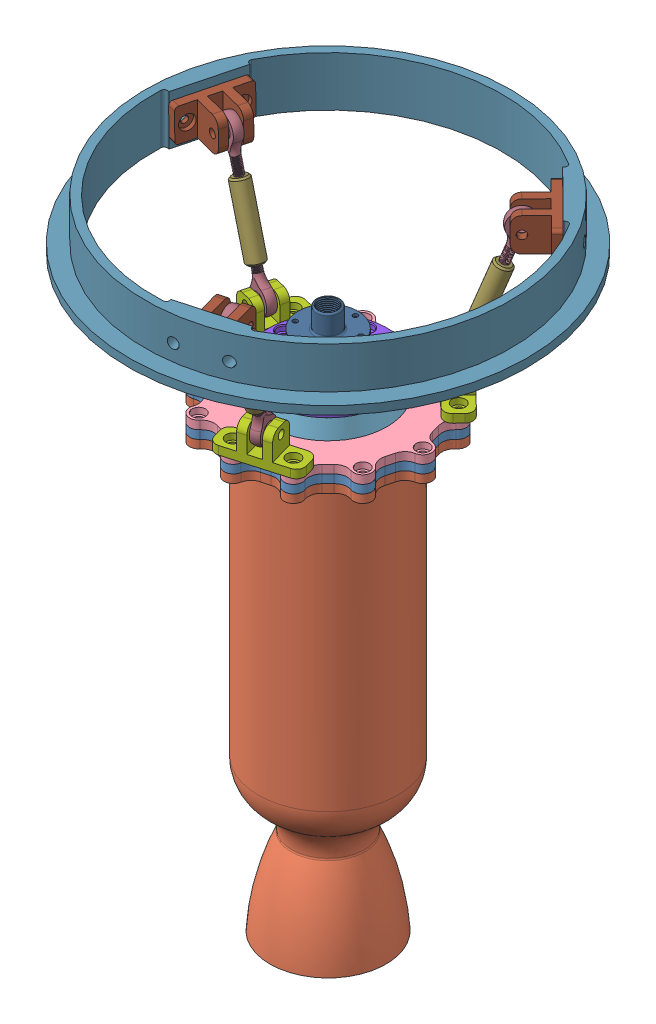
SolidWorks assembly 000014-R02_REMOVE_BEFORE_FLIGHT_ASSM, configuration Default. Lengths in mm.
Overall size (431.04 487.19 431.04).
30 component instances, 14 part files, 22 mates.
Components (placement in the parent):
- 000030-R02_FILM_COOLING_VOLUTE-2: 000030-R02_FILM_COOLING_VOLUTE [Default] at (-8.7806 254.8412 0) x (-0.965926 0 -0.258819) z (0.258819 0 -0.965926) size (156.79 34.88 257.08)
- 000001-R05_RBF_TCA-2: 000001-R05_RBF_TCA [Default] at (-8.7806 -14.701 0) x (0 -1 0) z (0 0 1) size (343.5 185.64 158.75)
- 000015-R05_PINTLE_INJECT_ASSM-1: 000015-R05_PINTLE_INJECT_ASSM [Default] at (86.4435 164.1172 71.5928) x (-0.866025 0 0.5) z (-0.5 0 -0.866025) size (158.75 36.86 158.75)
  - 000033-R01_PINTLE_BOTTOM_PLATE-1: 000033-R01_PINTLE_BOTTOM_PLATE [Default] at (46.67 88.1839 109.6132) size (87.7 15.24 87.7)
  - 000032-R02_PINTLE_MIDDLE_PLATE-1: 000032-R02_PINTLE_MIDDLE_PLATE [Default] at (46.67 92.7382 109.6132) size (158.75 29.57 158.75)
  - 000031-R01_PINTLE_UPPER_PLATE-1: 000031-R01_PINTLE_UPPER_PLATE [Default] at (46.67 125.0393 109.6132) size (90.17 15.27 90.17)
  - MISUMI_MSBH6-20-1: MISUMI_MSBH6-20 [Default] at (8.57 121.0393 109.6132) x (0 -1 0) z (0 0 1) size (31 9 9)
- engine-side-clevis-1: engine-side-clevis [Default] at (-7.5695 273.8912 0.6838) x (0.693392 0 -0.72056) z (0.72056 0 0.693392) size (19.05 25.4 57.15)
- 000012_R04_ASI_ASSEM-1: 000012_R04_ASI_ASSEM [Default] at (-8.7806 251.1654 0) x (-0.959573 0 0.281459) z (-0.281459 0 -0.959573) size (117.68 93.77 117.68)
  - 000011-R02_ASI_TOP-1: 000011-R02_ASI_TOP [Default] at (0 37.9912 0) x (-0.924896 0 -0.380219) z (0.380219 0 -0.924896) size (90.17 60.14 90.17)
  - 000011-R02_ASI_BOTTOM-1: 000011-R02_ASI_BOTTOM [Default] at (0 4.4632 0) x (0.915191 0 -0.40302) z (0.40302 0 0.915191) size (30.48 24.13 30.48)
  - 000010-R02_ASI-1: 000010-R02_ASI [Default] at (0 63.3912 0) x (-0.133168 0 -0.991093) z (0.991093 0 -0.133168) size (45.72 18.88 45.72)
- 000061-R01_THRUST_MOUNT_ASSM-6: 000061-R01_THRUST_MOUNT_ASSM [Default] at (108.3978 328.6699 -153.5919) x (-0.197262 0.979436 -0.042345) z (0.576802 0.15088 0.802829) size (118.32 96.83 60.51) (flexible)
  - 000029-R01_LAUNCH_MOUNT_CLEVIS-1: 000029-R01_LAUNCH_MOUNT_CLEVIS [Default] at (58.7034 52.1122 43.2404) x (0.980239 -0.133241 0.146211) z (-0.165429 -0.146887 0.975222) size (31.75 38.1 50.8)
  - THREADED_ROD-1: THREADED_ROD [Default] at (36.9792 86.6959 44.7642) x (0.299604 0.419939 -0.856673) z (0.366938 0.778134 0.509768) size (12.7 50.8 12.7)
  - 8405K111_THRUST-RATED BALL JOINT ROD END-1: 8405K111_THRUST-RATED BALL JOINT ROD END [8405K111] at (-12.0929 112.7217 40.36) x (0.441581 0.869836 0.219984) z (-0.171501 -0.158832 0.972296) size (19.88 46.6 9.53)
  - 8405K111_THRUST-RATED BALL JOINT ROD END-2: 8405K111_THRUST-RATED BALL JOINT ROD END [8405K111] at (47.1332 81.3106 45.6756) x (-0.443891 -0.871932 -0.206628) z (-0.165429 -0.146887 0.975222) size (19.88 46.6 9.53)
- engine-side-clevis-6: engine-side-clevis [Default] at (-9.9782 273.8912 0.7069) x (0.277328 0 0.960775) z (-0.960775 0 0.277328) size (19.05 25.4 57.15)
- engine-side-clevis-7: engine-side-clevis [Default] at (-8.7939 273.8912 -1.3907) x (-0.97072 0 -0.240215) z (0.240215 0 -0.97072) size (19.05 25.4 57.15)
- 000061-R01_THRUST_MOUNT_ASSM-7: 000061-R01_THRUST_MOUNT_ASSM [Default] at (65.6447 328.6699 178.2754) x (0.135303 0.979436 -0.149661) z (-0.983671 0.15088 0.098111) size (118.32 96.83 60.51) (flexible)
  - 000029-R01_LAUNCH_MOUNT_CLEVIS-1: 000029-R01_LAUNCH_MOUNT_CLEVIS [Default] at (58.7034 52.1122 43.2404) x (0.980239 -0.133241 0.146211) z (-0.165429 -0.146887 0.975222) size (31.75 38.1 50.8)
  - THREADED_ROD-1: THREADED_ROD [Default] at (36.7589 86.8127 44.7445) x (0.039613 0.238881 0.97024) z (-0.472056 -0.851338 0.22888) size (12.7 50.8 12.7)
  - 8405K111_THRUST-RATED BALL JOINT ROD END-1: 8405K111_THRUST-RATED BALL JOINT ROD END [8405K111] at (-12.0929 112.7217 40.36) x (0.441581 0.869836 0.219984) z (-0.171501 -0.158832 0.972296) size (19.88 46.6 9.53)
  - 8405K111_THRUST-RATED BALL JOINT ROD END-2: 8405K111_THRUST-RATED BALL JOINT ROD END [8405K111] at (47.1332 81.3106 45.6756) x (-0.443891 -0.871932 -0.206628) z (-0.165429 -0.146887 0.975222) size (19.88 46.6 9.53)
- 000061-R01_THRUST_MOUNT_ASSM-8: 000061-R01_THRUST_MOUNT_ASSM [Default] at (-200.3842 328.6699 -24.6835) x (0.061959 0.979436 0.192007) z (0.406869 0.15088 -0.90094) size (124.54 97.67 60.51) (flexible)
  - 000029-R01_LAUNCH_MOUNT_CLEVIS-1: 000029-R01_LAUNCH_MOUNT_CLEVIS [Default] at (58.7034 52.1122 43.2404) x (-0.980239 0.133241 -0.146211) z (0.165429 0.146887 -0.975222) size (31.75 38.1 50.8)
  - THREADED_ROD-1: THREADED_ROD [Default] at (36.7628 86.8107 44.7448) x (0.181458 0.17849 -0.967065) z (0.437583 0.866015 0.241947) size (12.7 50.8 12.7)
  - 8405K111_THRUST-RATED BALL JOINT ROD END-1: 8405K111_THRUST-RATED BALL JOINT ROD END [8405K111] at (-12.0929 112.7217 40.36) x (0.441581 0.869836 0.219984) z (-0.171501 -0.158832 0.972296) size (19.88 46.6 9.53)
  - 8405K111_THRUST-RATED BALL JOINT ROD END-2: 8405K111_THRUST-RATED BALL JOINT ROD END [8405K111] at (47.1332 81.3106 45.6756) x (0.443891 0.871932 0.206628) z (0.165429 0.146887 -0.975222) size (19.88 46.6 9.53)
- 000066-R01_THRUST_MOUNT-1: 000066-R01_THRUST_MOUNT [Default] at (-8.7806 366.7438 0) x (0.702595 0 -0.71159) z (0.71159 0 0.702595) size (304.8 38.1 304.8)
Mates (geometry in assembly coordinates):
- Concentric22: concentric aligned: cylinder of 000030-R02_FILM_COOLING_VOLUTE-2 through (63.6094 267.5412 0) axis (0 1 0) radius 4; cylinder of 000001-R05_RBF_TCA-2 through (63.6094 261.1912 0) axis (0 1 0) radius 4
- Coincident11: coincident anti-aligned: plane of 000030-R02_FILM_COOLING_VOLUTE-2 through (-66.4686 261.1912 -15.4575) normal (0 -1 0); plane of 000001-R05_RBF_TCA-2 through (70.5944 261.1912 0) normal (0 1 0)
- Concentric40: concentric anti-aligned: cylinder of 000030-R02_FILM_COOLING_VOLUTE-2 through (-8.7806 299.8925 0) axis (0 1 0) radius 43.848; cylinder of 000015-R05_PINTLE_INJECT_ASSM-1/000033-R01_PINTLE_BOTTOM_PLATE-1 through (-8.7806 252.3012 0) axis (0 -1 0) radius 43.848
- Coincident29: coincident anti-aligned: plane of 000030-R02_FILM_COOLING_VOLUTE-2 through (-51.1345 267.5412 -11.3487) normal (0 1 0); plane of 000015-R05_PINTLE_INJECT_ASSM-1/000032-R02_PINTLE_MIDDLE_PLATE-1 through (-77.5213 267.5412 39.6875) normal (0 -1 0)
- Coincident65: coincident anti-aligned: plane of 000015-R05_PINTLE_INJECT_ASSM-1/000032-R02_PINTLE_MIDDLE_PLATE-1 through (-77.5213 273.8912 39.6875) normal (0 1 0); plane of engine-side-clevis-1 through (-7.5695 273.8912 0.6838) normal (0 -1 0)
- Coincident70: coincident anti-aligned: plane of 000015-R05_PINTLE_INJECT_ASSM-1/000031-R01_PINTLE_UPPER_PLATE-1 through (-16.4795 289.1566 4.445) normal (0 1 0); plane of 000012_R04_ASI_ASSEM-1/000011-R02_ASI_TOP-1 through (36.0575 289.1566 4.7127) normal (0 -1 0)
- Concentric88: concentric aligned: cylinder of 000015-R05_PINTLE_INJECT_ASSM-1/000031-R01_PINTLE_UPPER_PLATE-1 through (6.7161 289.1566 -34.8061) axis (0 1 0) radius 5; cylinder of 000012_R04_ASI_ASSEM-1/000011-R02_ASI_TOP-1 through (6.7161 294.2366 -34.8061) axis (0 1 0) radius 4.953
- Concentric89: concentric aligned: cylinder of 000015-R05_PINTLE_INJECT_ASSM-1/000031-R01_PINTLE_UPPER_PLATE-1 through (24.215 289.1566 -19.05) axis (0 1 0) radius 5; cylinder of 000012_R04_ASI_ASSEM-1/000011-R02_ASI_TOP-1 through (24.215 294.2366 -19.05) axis (0 1 0) radius 4.953
- Concentric91: concentric anti-aligned: cylinder of 000030-R02_FILM_COOLING_VOLUTE-2 through (53.911 267.5412 -36.195) axis (0 1 0) radius 4; cylinder of 000015-R05_PINTLE_INJECT_ASSM-1/000032-R02_PINTLE_MIDDLE_PLATE-1 through (53.911 273.8912 -36.195) axis (0 -1 0) radius 5.1587
- Concentric93: concentric anti-aligned: cylinder of 000001-R05_RBF_TCA-2 through (53.911 261.1912 36.195) axis (0 1 0) radius 4; cylinder of 000015-R05_PINTLE_INJECT_ASSM-1/000032-R02_PINTLE_MIDDLE_PLATE-1 through (53.911 273.8912 36.195) axis (0 -1 0) radius 5.1587
- Concentric95: concentric aligned: cylinder of engine-side-clevis-1 through (20.2739 292.9412 -69.4611) axis (0.72056 0 0.693392) radius 3.175; cylinder of 000061-R01_THRUST_MOUNT_ASSM-6/8405K111_THRUST-RATED BALL JOINT ROD END-1 through (37.4323 292.9412 -52.9497) axis (0.72056 0 0.693392) radius 3.175
- Coincident73: coincident aligned: plane of engine-side-clevis-1 through (-7.5695 273.8912 0.6838) normal (0.72056 0 0.693392); plane of 000061-R01_THRUST_MOUNT_ASSM-6/8405K111_THRUST-RATED BALL JOINT ROD END-1 through (44.7076 307.8169 -53.6416) normal (0.72056 0 0.693392)
- Coincident75: coincident anti-aligned: plane of 000015-R05_PINTLE_INJECT_ASSM-1/000032-R02_PINTLE_MIDDLE_PLATE-1 through (-77.5213 273.8912 39.6875) normal (0 1 0); plane of engine-side-clevis-1 through (-7.5695 273.8912 0.6838) normal (0 -1 0)
- Concentric100: concentric aligned: cylinder of engine-side-clevis-7 through (-83.4628 292.9412 9.5686) axis (0.240215 0 -0.97072) radius 3.175; cylinder of 000061-R01_THRUST_MOUNT_ASSM-8/8405K111_THRUST-RATED BALL JOINT ROD END-1 through (-77.7427 292.9412 -13.5466) axis (0.240215 0 -0.97072) radius 3.175
- Coincident76: coincident aligned: plane of engine-side-clevis-7 through (-8.7939 273.8912 -1.3907) normal (0.240215 0 -0.97072); plane of 000061-R01_THRUST_MOUNT_ASSM-8/8405K111_THRUST-RATED BALL JOINT ROD END-1 through (-81.9797 307.8169 -19.5013) normal (0.240215 0 -0.97072)
- Coincident78: coincident aligned: plane of engine-side-clevis-6 through (-9.9782 273.8912 0.7069) normal (-0.960775 0 0.277328); plane of 000061-R01_THRUST_MOUNT_ASSM-7/8405K111_THRUST-RATED BALL JOINT ROD END-1 through (10.9304 307.8169 73.1429) normal (-0.960775 0 0.277328)
- Concentric101: concentric aligned: cylinder of engine-side-clevis-6 through (36.8473 292.9412 59.8924) axis (-0.960775 0 0.277328) radius 3.175; cylinder of 000061-R01_THRUST_MOUNT_ASSM-7/8405K111_THRUST-RATED BALL JOINT ROD END-1 through (13.9688 292.9412 66.4963) axis (-0.960775 0 0.277328) radius 3.175
- Coincident79: coincident anti-aligned: plane of 000061-R01_THRUST_MOUNT_ASSM-6/000029-R01_LAUNCH_MOUNT_CLEVIS-1 through (80.4492 385.7102 -90.3717) normal (0.702595 0 -0.71159); plane of 000066-R01_THRUST_MOUNT-1 through (62.3747 366.7438 -108.2178) normal (-0.702595 0 0.71159)
- Coincident80: coincident anti-aligned: plane of 000061-R01_THRUST_MOUNT_ASSM-7/000029-R01_LAUNCH_MOUNT_CLEVIS-1 through (24.8688 385.7102 122.4611) normal (0.264957 0 0.96426); plane of 000066-R01_THRUST_MOUNT-1 through (49.3612 366.7438 115.7311) normal (-0.264957 0 -0.96426)
- Coincident81: coincident anti-aligned: plane of 000061-R01_THRUST_MOUNT_ASSM-8/000029-R01_LAUNCH_MOUNT_CLEVIS-1 through (-131.6597 385.7102 -32.0894) normal (-0.967552 0 -0.252671); plane of 000066-R01_THRUST_MOUNT-1 through (-138.0775 366.7438 -7.5133) normal (0.967552 0 0.252671)
- Concentric102: concentric anti-aligned: cylinder of 000001-R05_RBF_TCA-2 through (-8.7806 221.7735 0) axis (0 1 0) radius 53.373; cylinder of 000066-R01_THRUST_MOUNT-1 through (-8.7806 404.8438 0) axis (0 -1 0) radius 152.4
- Concentric104: concentric aligned: cylinder of 000061-R01_THRUST_MOUNT_ASSM-6/000029-R01_LAUNCH_MOUNT_CLEVIS-1 through (88.4137 385.7938 -73.5842) axis (-0.702595 0 0.71159) radius 2.5527; cylinder of 000066-R01_THRUST_MOUNT-1 through (92.8752 385.7938 -78.1028) axis (-0.702595 0 0.71159) radius 4
